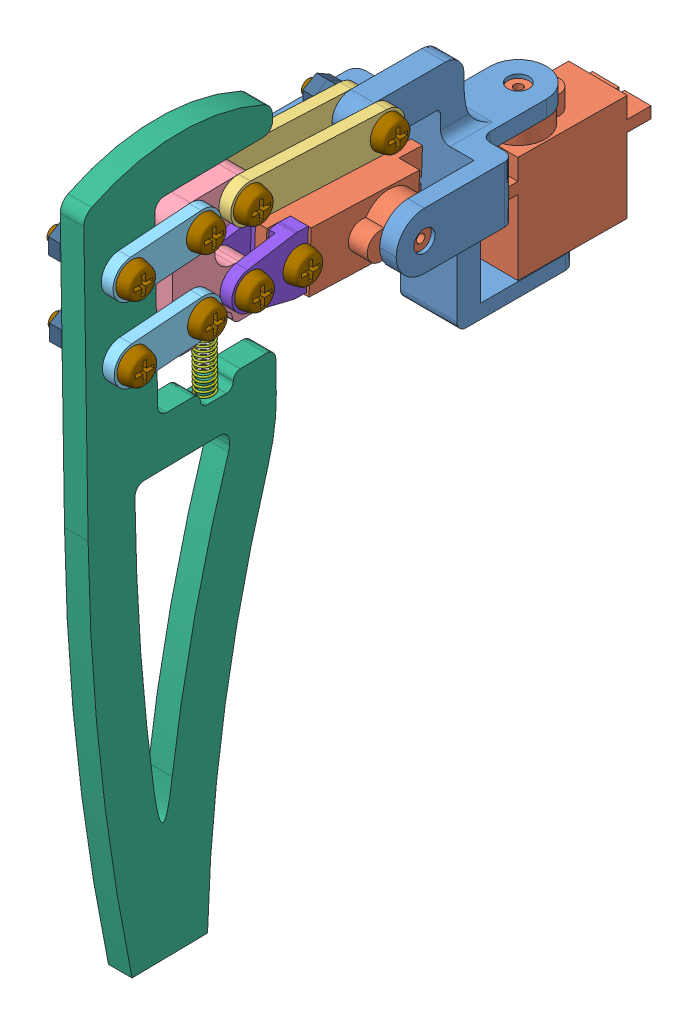
SolidWorks assembly leg_v2_2, configuration Default. Lengths in mm.
Overall size (33.5 150.6 116.51).
37 component instances, 10 part files, 84 mates.
Components (placement in the parent):
- leg2_v2-1: leg2_v2 [Default] at (2.6504 15.2081 48.4178) x (1 0 0) z (0 0.000039 1) size (33.5 47.5 45)
- servo-1: servo [Default] at (14.8483 18.6078 40.7193) x (0.008296 -0.000039 -0.999966) z (0.999966 0 0.008296) size (33 29.3 12.5)
- servo-2: servo [Default] at (-8.3496 48.7202 60.9369) x (0 0.037483 0.999297) z (0 0.999297 -0.037483) size (33 29.3 12.5)
- leg_bond2_f_v2-1: leg_bond2_f_v2 [Default] at (13.6504 58.7089 67.4161) x (0 0.045708 0.998955) z (0 -0.998955 0.045708) size (37 2.5 8)
- leg_bond2_f_v2-2: leg_bond2_f_v2 [Default] at (6.1504 58.7089 67.4161) x (0 0.045708 0.998955) z (0 -0.998955 0.045708) size (37 2.5 8)
- leg1_seg1_v2-1: leg1_seg1_v2 [Default] at (6.1504 36.8196 110.0267) x (0 0.01554 -0.999879) z (0 -0.999879 -0.01554) size (18 5 27)
- leg_bond1_f_v2-1: leg_bond1_f_v2 [Default] at (3.6504 58.741 121.3345) x (0 0.075902 -0.997115) z (0 -0.997115 -0.075902) size (23 2.5 8)
- leg_bond1_f_v2-2: leg_bond1_f_v2 [Default] at (11.1504 42.7429 121.0859) x (0 0.075902 -0.997115) z (0 -0.997115 -0.075902) size (23 2.5 8)
- leg_bond1_f_v2-3: leg_bond1_f_v2 [Default] at (3.6504 42.7429 121.0859) x (0 0.075902 -0.997115) z (0 -0.997115 -0.075902) size (23 2.5 8)
- leg_bond1_f_v2-4: leg_bond1_f_v2 [Default] at (11.1504 58.741 121.3345) x (0 0.075902 -0.997115) z (0 -0.997115 -0.075902) size (23 2.5 8)
- leg1_v2-1: leg1_v2 [Default] at (6.1504 -72.3597 126.7978) x (0 0.01554 -0.999879) z (0 -0.999879 -0.01554) size (40 5.02 150)
- spring2-7: spring2 [Default] at (8.6504 25.0559 100.8086) x (1 0 0) z (0 -0.01554 0.999879) size (4.08 15.71 4.5)
- leg3_f_v2-3: leg3_f_v2 [Default] at (3.6504 37.5908 84.3705) x (0 0.999297 -0.037483) z (0 -0.037483 -0.999297) size (12 3.8 16)
- leg3_f_v2-4: leg3_f_v2 [Default] at (13.6504 49.5823 83.9207) x (0 -0.999297 0.037483) z (0 -0.037483 -0.999297) size (12 3.8 16)
- bolt-1: bolt [Default] at (13.6504 58.7089 67.4161) x (0 -1 0) z (0 0 1) size (6.83 19 6.83)
- bolt-2: bolt [Default] at (13.6504 59.879 106.3846) x (0 -1 0) z (0 0 1) size (6.83 19 6.83)
- bolt-3: bolt [Default] at (13.6504 43.881 106.136) x (0 -1 0) z (0 0 1) size (6.83 19 6.83)
- bolt-4: bolt [Default] at (13.6504 44.0364 96.1372) x (0 -1 0) z (0 0 1) size (6.83 19 6.83)
- bolt-5: bolt [Default] at (13.6504 58.741 121.3345) x (0 -1 0) z (0 0 1) size (6.83 19 6.83)
- bolt-6: bolt [Default] at (13.6504 60.0344 96.3858) x (0 -1 0) z (0 0 1) size (6.83 19 6.83)
- bolt-7: bolt [Default] at (13.6504 42.7429 121.0859) x (0 -1 0) z (0 0 1) size (6.83 19 6.83)
- bolt-8: bolt [Default] at (13.6504 43.6521 85.8944) x (0 -1 0) z (0 0 1) size (6.83 19 6.83)
- nut-1: nut [Default] at (1.2504 43.881 106.136) x (0 1 0) z (0 0 1) size (6.7 2.4 5.8)
- nut-2: nut [Default] at (3.6504 44.0364 96.1372) x (0 1 0) z (0 0 1) size (6.7 2.4 5.8)
- nut-3: nut [Default] at (3.6504 42.7429 121.0859) x (0 1 0) z (0 0 1) size (6.7 2.4 5.8)
- nut-4: nut [Default] at (3.6504 43.881 106.136) x (0 1 0) z (0 0 1) size (6.7 2.4 5.8)
- nut-5: nut [Default] at (1.2504 44.0364 96.1372) x (0 1 0) z (0 0 1) size (6.7 2.4 5.8)
- nut-6: nut [Default] at (3.6504 60.0344 96.3858) x (0 1 0) z (0 0 1) size (6.7 2.4 5.8)
- nut-7: nut [Default] at (1.2504 60.0344 96.3858) x (0 1 0) z (0 0 1) size (6.7 2.4 5.8)
- nut-8: nut [Default] at (3.6504 58.7089 67.4161) x (0 1 0) z (0 0 1) size (6.7 2.4 5.8)
- nut-9: nut [Default] at (1.2504 58.7089 67.4161) x (0 1 0) z (0 0 1) size (6.7 2.4 5.8)
- nut-10: nut [Default] at (3.6504 43.6521 85.8944) x (0 1 0) z (0 0 1) size (6.7 2.4 5.8)
- nut-11: nut [Default] at (3.6504 59.879 106.3846) x (0 1 0) z (0 0 1) size (6.7 2.4 5.8)
- nut-12: nut [Default] at (1.2504 59.879 106.3846) x (0 1 0) z (0 0 1) size (6.7 2.4 5.8)
- nut-13: nut [Default] at (3.6504 58.741 121.3345) x (0 1 0) z (0 0 1) size (6.7 2.4 5.8)
- nut-14: nut [Default] at (1.2504 42.7429 121.0859) x (0 1 0) z (0 0 1) size (6.7 2.4 5.8)
- nut-15: nut [Default] at (1.2504 58.741 121.3345) x (0 1 0) z (0 0 1) size (6.7 2.4 5.8)
Mates (geometry in assembly coordinates):
- Concentric2: concentric anti-aligned: cylinder of leg2_v2-1 through (8.6504 15.2066 34.4178) axis (0 1 -0.000039) radius 2.25; cylinder of servo-1 through (8.6504 47.9076 34.4166) axis (0 -1 0.000039) radius 2.3
- Coincident2: coincident anti-aligned: plane of leg2_v2-1 through (14.6504 45.2074 28.4167) normal (0 -1 0.000039); plane of servo-1 through (8.6743 45.2075 31.5418) normal (0 1 -0.000039)
- Concentric3: concentric anti-aligned: cylinder of leg2_v2-1 through (-11.7506 42.7089 67.4168) axis (1 0 0) radius 2.25; cylinder of servo-2 through (20.9504 42.7089 67.4168) axis (-1 0 0) radius 2.3
- Coincident3: coincident anti-aligned: plane of leg2_v2-1 through (18.2504 48.7091 73.4165) normal (-1 0 0); plane of servo-2 through (18.2504 42.8166 70.2897) normal (1 0 0)
- Concentric4: concentric anti-aligned: cylinder of leg2_v2-1 through (1.5542 58.7089 67.4161) axis (1 0 0) radius 1.625; cylinder of leg_bond2_f_v2-1 through (18.2466 58.7089 67.4161) axis (-1 0 0) radius 1.625
- Coincident4: coincident anti-aligned: plane of leg2_v2-1 through (11.1504 48.7083 53.4165) normal (1 0 0); plane of leg_bond2_f_v2-1 through (11.1504 58.7089 67.4161) normal (-1 0 0)
- Concentric5: concentric anti-aligned: cylinder of leg2_v2-1 through (1.5542 58.7089 67.4161) axis (1 0 0) radius 1.625; cylinder of leg_bond2_f_v2-2 through (10.7466 58.7089 67.4161) axis (-1 0 0) radius 1.625
- Coincident5: coincident anti-aligned: plane of leg2_v2-1 through (6.1504 48.7083 53.4165) normal (-1 0 0); plane of leg_bond2_f_v2-2 through (6.1504 58.7089 67.4161) normal (1 0 0)
- Parallel2: parallel aligned: plane of leg_bond2_f_v2-1 through (11.1504 54.7131 67.599) normal (0 -0.998955 0.045708); plane of leg_bond2_f_v2-2 through (3.6504 54.7131 67.599) normal (0 -0.998955 0.045708)
- Coincident8: coincident anti-aligned: plane of leg_bond2_f_v2-1 through (11.1504 58.7089 67.4161) normal (-1 0 0); plane of leg1_seg1_v2-1 through (11.1504 36.8196 110.0267) normal (1 0 0)
- Coincident9: coincident anti-aligned: plane of leg_bond2_f_v2-2 through (6.1504 58.7089 67.4161) normal (1 0 0); plane of leg1_seg1_v2-1 through (6.1504 36.8196 110.0267) normal (-1 0 0)
- Concentric8: concentric aligned: cylinder of leg_bond2_f_v2-1 through (18.2466 60.0344 96.3858) axis (-1 0 0) radius 1.625; cylinder of leg1_seg1_v2-1 through (11.1504 60.0344 96.3858) axis (-1 0 0) radius 1.625
- Concentric9: concentric aligned: cylinder of leg_bond2_f_v2-2 through (10.7466 60.0344 96.3858) axis (-1 0 0) radius 1.625; cylinder of leg1_seg1_v2-1 through (11.1504 60.0344 96.3858) axis (-1 0 0) radius 1.625
- Concentric12: concentric anti-aligned: cylinder of leg1_seg1_v2-1 through (11.1504 59.879 106.3846) axis (-1 0 0) radius 1.625; cylinder of leg_bond1_f_v2-1 through (-0.5922 59.879 106.3846) axis (1 0 0) radius 1.5
- Coincident15: coincident anti-aligned: plane of leg1_seg1_v2-1 through (6.1504 36.8196 110.0267) normal (-1 0 0); plane of leg_bond1_f_v2-1 through (6.1504 58.741 121.3345) normal (1 0 0)
- Concentric13: concentric anti-aligned: cylinder of leg1_seg1_v2-1 through (11.1504 59.879 106.3846) axis (-1 0 0) radius 1.625; cylinder of leg_bond1_f_v2-4 through (6.9078 59.879 106.3846) axis (1 0 0) radius 1.5
- Coincident16: coincident anti-aligned: plane of leg1_seg1_v2-1 through (11.1504 36.8196 110.0267) normal (1 0 0); plane of leg_bond1_f_v2-4 through (11.1504 58.741 121.3345) normal (-1 0 0)
- Parallel3: parallel aligned: plane of leg_bond1_f_v2-1 through (6.1504 54.7525 121.0309) normal (0 -0.997115 -0.075902); plane of leg_bond1_f_v2-4 through (13.6504 54.7525 121.0309) normal (0 -0.997115 -0.075902)
- Concentric14: concentric anti-aligned: cylinder of leg1_seg1_v2-1 through (11.1504 43.881 106.136) axis (-1 0 0) radius 1.625; cylinder of leg_bond1_f_v2-3 through (-0.5922 43.881 106.136) axis (1 0 0) radius 1.5
- Coincident18: coincident anti-aligned: plane of leg1_seg1_v2-1 through (6.1504 36.8196 110.0267) normal (-1 0 0); plane of leg_bond1_f_v2-3 through (6.1504 42.7429 121.0859) normal (1 0 0)
- Concentric15: concentric anti-aligned: cylinder of leg1_seg1_v2-1 through (11.1504 43.881 106.136) axis (-1 0 0) radius 1.625; cylinder of leg_bond1_f_v2-2 through (6.9078 43.881 106.136) axis (1 0 0) radius 1.5
- Coincident19: coincident anti-aligned: plane of leg1_seg1_v2-1 through (11.1504 36.8196 110.0267) normal (1 0 0); plane of leg_bond1_f_v2-2 through (11.1504 42.7429 121.0859) normal (-1 0 0)
- Parallel4: parallel aligned: plane of leg_bond1_f_v2-2 through (13.6504 38.7545 120.7823) normal (0 -0.997115 -0.075902); plane of leg_bond1_f_v2-3 through (6.1504 38.7545 120.7823) normal (0 -0.997115 -0.075902)
- Concentric16: concentric aligned: cylinder of leg_bond1_f_v2-1 through (-0.5922 58.741 121.3345) axis (1 0 0) radius 1.5; cylinder of leg1_v2-1 through (1.5542 58.741 121.3345) axis (1 0 0) radius 1.625
- Concentric17: concentric aligned: cylinder of leg_bond1_f_v2-4 through (6.9078 58.741 121.3345) axis (1 0 0) radius 1.5; cylinder of leg1_v2-1 through (1.5542 58.741 121.3345) axis (1 0 0) radius 1.625
- Concentric18: concentric aligned: cylinder of leg_bond1_f_v2-3 through (-0.5922 42.7429 121.0859) axis (1 0 0) radius 1.5; cylinder of leg1_v2-1 through (1.5542 42.7429 121.0859) axis (1 0 0) radius 1.625
- Concentric19: concentric aligned: cylinder of leg_bond1_f_v2-2 through (6.9078 42.7429 121.0859) axis (1 0 0) radius 1.5; cylinder of leg1_v2-1 through (1.5542 42.7429 121.0859) axis (1 0 0) radius 1.625
- Coincident21: coincident anti-aligned: plane of leg_bond1_f_v2-2 through (11.1504 42.7429 121.0859) normal (-1 0 0); plane of leg1_v2-1 through (11.1504 35.4381 108.4708) normal (1 0 0)
- Coincident34: coincident anti-aligned: plane of leg1_v2-1 through (-1.4654 25.0015 104.3081) normal (0 0.999879 0.01554); plane of spring2-7 through (8.6504 25.0559 100.8086) normal (0 -0.999879 -0.01554)
- Concentric30: concentric anti-aligned: cylinder of leg1_v2-1 through (8.6504 28.0556 100.8552) axis (0 -0.999879 -0.01554) radius 1.375; line of spring2-7 through (8.6504 25.0559 100.8086) axis (0 0.999879 0.01554)
- Coincident37: coincident anti-aligned: plane of leg1_seg1_v2-1 through (11.1504 39.9047 104.574) normal (0 -0.999879 -0.01554); plane of spring2-7 through (8.6504 39.9597 101.0402) normal (0 0.999879 0.01554)
- Concentric31: concentric aligned: cylinder of leg1_seg1_v2-1 through (11.1504 44.0364 96.1372) axis (-1 0 0) radius 1.625; cylinder of leg3_f_v2-3 through (6.1504 44.0364 96.1372) axis (-1 0 0) radius 1.5
- Coincident38: coincident anti-aligned: plane of servo-2 through (7.4504 49.7698 88.9172) normal (-1 0 0); plane of leg3_f_v2-3 through (7.4504 37.5908 84.3705) normal (1 0 0)
- Coincident39: coincident aligned: plane of servo-2 through (14.2504 48.7202 60.9369) normal (0 0.999297 -0.037483); plane of leg3_f_v2-3 through (6.1504 49.5823 83.9207) normal (0 0.999297 -0.037483)
- Concentric32: concentric anti-aligned: cylinder of leg1_seg1_v2-1 through (11.1504 44.0364 96.1372) axis (-1 0 0) radius 1.625; cylinder of leg3_f_v2-4 through (11.1504 44.0364 96.1372) axis (1 0 0) radius 1.5
- Coincident41: coincident aligned: plane of servo-2 through (14.2504 48.7202 60.9369) normal (0 0.999297 -0.037483); plane of leg3_f_v2-4 through (11.1504 49.5823 83.9207) normal (0 0.999297 -0.037483)
- Coincident42: coincident anti-aligned: plane of servo-2 through (9.8504 49.7698 88.9172) normal (1 0 0); plane of leg3_f_v2-4 through (9.8504 49.5823 83.9207) normal (-1 0 0)
- Coincident43: coincident anti-aligned: plane of servo-2 through (14.2504 49.5823 83.9207) normal (0 0.037483 0.999297); plane of leg3_f_v2-4 through (11.1504 49.5823 83.9207) normal (0 -0.037483 -0.999297)
- Concentric33: concentric anti-aligned: cylinder of leg_bond2_f_v2-1 through (18.2466 58.7089 67.4161) axis (-1 0 0) radius 1.625; cylinder of bolt-1 through (-2.8496 58.7089 67.4161) axis (1 0 0) radius 1.5
- Coincident44: coincident anti-aligned: plane of leg_bond2_f_v2-1 through (13.6504 58.7089 67.4161) normal (1 0 0); plane of bolt-1 through (13.6504 58.7089 67.4161) normal (-1 0 0)
- Concentric34: concentric anti-aligned: cylinder of leg_bond2_f_v2-1 through (18.2466 60.0344 96.3858) axis (-1 0 0) radius 1.625; cylinder of bolt-6 through (-2.8496 60.0344 96.3858) axis (1 0 0) radius 1.5
- Coincident45: coincident anti-aligned: plane of leg_bond2_f_v2-1 through (13.6504 58.7089 67.4161) normal (1 0 0); plane of bolt-6 through (13.6504 60.0344 96.3858) normal (-1 0 0)
- Concentric35: concentric aligned: cylinder of leg3_f_v2-4 through (11.1504 44.0364 96.1372) axis (1 0 0) radius 1.5; cylinder of bolt-4 through (-2.8496 44.0364 96.1372) axis (1 0 0) radius 1.5
- Coincident46: coincident anti-aligned: plane of leg3_f_v2-4 through (13.6504 44.0364 96.1372) normal (1 0 0); plane of bolt-4 through (13.6504 44.0364 96.1372) normal (-1 0 0)
- Concentric36: concentric aligned: cylinder of leg_bond1_f_v2-4 through (6.9078 59.879 106.3846) axis (1 0 0) radius 1.5; cylinder of bolt-2 through (-2.8496 59.879 106.3846) axis (1 0 0) radius 1.5
- Coincident47: coincident anti-aligned: plane of leg_bond1_f_v2-2 through (13.6504 42.7429 121.0859) normal (1 0 0); plane of bolt-2 through (13.6504 59.879 106.3846) normal (-1 0 0)
- Concentric37: concentric aligned: cylinder of leg_bond1_f_v2-2 through (6.9078 43.881 106.136) axis (1 0 0) radius 1.5; cylinder of bolt-3 through (-2.8496 43.881 106.136) axis (1 0 0) radius 1.5
- Coincident48: coincident anti-aligned: plane of leg_bond1_f_v2-2 through (13.6504 42.7429 121.0859) normal (1 0 0); plane of bolt-3 through (13.6504 43.881 106.136) normal (-1 0 0)
- Concentric38: concentric aligned: cylinder of leg_bond1_f_v2-4 through (6.9078 58.741 121.3345) axis (1 0 0) radius 1.5; cylinder of bolt-5 through (-2.8496 58.741 121.3345) axis (1 0 0) radius 1.5
- Coincident49: coincident anti-aligned: plane of leg_bond1_f_v2-4 through (13.6504 58.741 121.3345) normal (1 0 0); plane of bolt-5 through (13.6504 58.741 121.3345) normal (-1 0 0)
- Concentric39: concentric aligned: cylinder of leg_bond1_f_v2-2 through (6.9078 42.7429 121.0859) axis (1 0 0) radius 1.5; cylinder of bolt-7 through (-2.8496 42.7429 121.0859) axis (1 0 0) radius 1.5
- Coincident50: coincident anti-aligned: plane of leg_bond1_f_v2-2 through (13.6504 42.7429 121.0859) normal (1 0 0); plane of bolt-7 through (13.6504 42.7429 121.0859) normal (-1 0 0)
- Concentric40: concentric anti-aligned: cylinder of leg3_f_v2-4 through (17.893 43.6521 85.8944) axis (-1 0 0) radius 1.5; cylinder of bolt-8 through (-2.8496 43.6521 85.8944) axis (1 0 0) radius 1.5
- Coincident51: coincident anti-aligned: plane of leg3_f_v2-4 through (13.6504 44.0364 96.1372) normal (1 0 0); plane of bolt-8 through (13.6504 43.6521 85.8944) normal (-1 0 0)
- Concentric41: concentric anti-aligned: cylinder of bolt-1 through (-2.8496 58.7089 67.4161) axis (1 0 0) radius 1.5; cylinder of nut-8 through (3.6504 58.7089 67.4161) axis (-1 0 0) radius 1.5
- Coincident52: coincident anti-aligned: plane of leg_bond2_f_v2-2 through (3.6504 58.7089 67.4161) normal (-1 0 0); plane of nut-8 through (3.6504 58.7089 67.4161) normal (1 0 0)
- Concentric42: concentric anti-aligned: cylinder of bolt-1 through (-2.8496 58.7089 67.4161) axis (1 0 0) radius 1.5; cylinder of nut-9 through (1.2504 58.7089 67.4161) axis (-1 0 0) radius 1.5
- Coincident53: coincident anti-aligned: plane of nut-8 through (1.2504 58.7089 67.4161) normal (-1 0 0); plane of nut-9 through (1.2504 58.7089 67.4161) normal (1 0 0)
- Concentric43: concentric anti-aligned: cylinder of bolt-6 through (-2.8496 60.0344 96.3858) axis (1 0 0) radius 1.5; cylinder of nut-6 through (3.6504 60.0344 96.3858) axis (-1 0 0) radius 1.5
- Coincident54: coincident anti-aligned: plane of leg_bond2_f_v2-2 through (3.6504 58.7089 67.4161) normal (-1 0 0); plane of nut-6 through (3.6504 60.0344 96.3858) normal (1 0 0)
- Concentric44: concentric anti-aligned: cylinder of bolt-6 through (-2.8496 60.0344 96.3858) axis (1 0 0) radius 1.5; cylinder of nut-7 through (1.2504 60.0344 96.3858) axis (-1 0 0) radius 1.5
- Coincident55: coincident anti-aligned: plane of nut-6 through (1.2504 60.0344 96.3858) normal (-1 0 0); plane of nut-7 through (1.2504 60.0344 96.3858) normal (1 0 0)
- Concentric45: concentric anti-aligned: cylinder of bolt-8 through (-2.8496 43.6521 85.8944) axis (1 0 0) radius 1.5; cylinder of nut-10 through (3.6504 43.6521 85.8944) axis (-1 0 0) radius 1.5
- Coincident56: coincident anti-aligned: plane of leg3_f_v2-3 through (3.6504 44.0364 96.1372) normal (-1 0 0); plane of nut-10 through (3.6504 43.6521 85.8944) normal (1 0 0)
- Concentric46: concentric anti-aligned: cylinder of bolt-2 through (-2.8496 59.879 106.3846) axis (1 0 0) radius 1.5; cylinder of nut-11 through (3.6504 59.879 106.3846) axis (-1 0 0) radius 1.5
- Coincident57: coincident anti-aligned: plane of leg_bond1_f_v2-1 through (3.6504 58.741 121.3345) normal (-1 0 0); plane of nut-11 through (3.6504 59.879 106.3846) normal (1 0 0)
- Concentric47: concentric anti-aligned: cylinder of bolt-2 through (-2.8496 59.879 106.3846) axis (1 0 0) radius 1.5; cylinder of nut-12 through (1.2504 59.879 106.3846) axis (-1 0 0) radius 1.5
- Coincident58: coincident anti-aligned: plane of nut-11 through (1.2504 59.879 106.3846) normal (-1 0 0); plane of nut-12 through (1.2504 59.879 106.3846) normal (1 0 0)
- Concentric48: concentric anti-aligned: cylinder of bolt-4 through (-2.8496 44.0364 96.1372) axis (1 0 0) radius 1.5; cylinder of nut-2 through (3.6504 44.0364 96.1372) axis (-1 0 0) radius 1.5
- Coincident59: coincident anti-aligned: plane of leg3_f_v2-3 through (3.6504 44.0364 96.1372) normal (-1 0 0); plane of nut-2 through (3.6504 44.0364 96.1372) normal (1 0 0)
- Concentric49: concentric anti-aligned: cylinder of bolt-4 through (-2.8496 44.0364 96.1372) axis (1 0 0) radius 1.5; cylinder of nut-5 through (1.2504 44.0364 96.1372) axis (-1 0 0) radius 1.5
- Coincident60: coincident anti-aligned: plane of nut-2 through (1.2504 44.0364 96.1372) normal (-1 0 0); plane of nut-5 through (1.2504 44.0364 96.1372) normal (1 0 0)
- Coincident61: coincident anti-aligned: cylinder of bolt-3 through (-2.8496 43.881 106.136) axis (1 0 0) radius 1.5; circle of nut-4
- Coincident62: coincident anti-aligned: plane of leg_bond1_f_v2-3 through (3.6504 42.7429 121.0859) normal (-1 0 0); plane of nut-4 through (3.6504 43.881 106.136) normal (1 0 0)
- Concentric50: concentric anti-aligned: cylinder of bolt-3 through (-2.8496 43.881 106.136) axis (1 0 0) radius 1.5; cylinder of nut-1 through (1.2504 43.881 106.136) axis (-1 0 0) radius 1.5
- Coincident63: coincident anti-aligned: plane of nut-1 through (1.2504 43.881 106.136) normal (1 0 0); plane of nut-4 through (1.2504 43.881 106.136) normal (-1 0 0)
- Concentric51: concentric anti-aligned: cylinder of bolt-5 through (-2.8496 58.741 121.3345) axis (1 0 0) radius 1.5; cylinder of nut-13 through (3.6504 58.741 121.3345) axis (-1 0 0) radius 1.5
- Coincident64: coincident anti-aligned: plane of leg_bond1_f_v2-1 through (3.6504 58.741 121.3345) normal (-1 0 0); plane of nut-13 through (3.6504 58.741 121.3345) normal (1 0 0)
- Concentric52: concentric anti-aligned: cylinder of bolt-5 through (-2.8496 58.741 121.3345) axis (1 0 0) radius 1.5; cylinder of nut-15 through (1.2504 58.741 121.3345) axis (-1 0 0) radius 1.5
- Coincident65: coincident anti-aligned: plane of nut-13 through (1.2504 58.741 121.3345) normal (-1 0 0); plane of nut-15 through (1.2504 58.741 121.3345) normal (1 0 0)
- Concentric53: concentric anti-aligned: cylinder of bolt-7 through (-2.8496 42.7429 121.0859) axis (1 0 0) radius 1.5; cylinder of nut-3 through (3.6504 42.7429 121.0859) axis (-1 0 0) radius 1.5
- Coincident66: coincident anti-aligned: plane of leg_bond1_f_v2-3 through (3.6504 42.7429 121.0859) normal (-1 0 0); plane of nut-3 through (3.6504 42.7429 121.0859) normal (1 0 0)
- Concentric54: concentric anti-aligned: cylinder of bolt-7 through (-2.8496 42.7429 121.0859) axis (1 0 0) radius 1.5; cylinder of nut-14 through (1.2504 42.7429 121.0859) axis (-1 0 0) radius 1.5
- Coincident67: coincident anti-aligned: plane of nut-3 through (1.2504 42.7429 121.0859) normal (-1 0 0); plane of nut-14 through (1.2504 42.7429 121.0859) normal (1 0 0)
